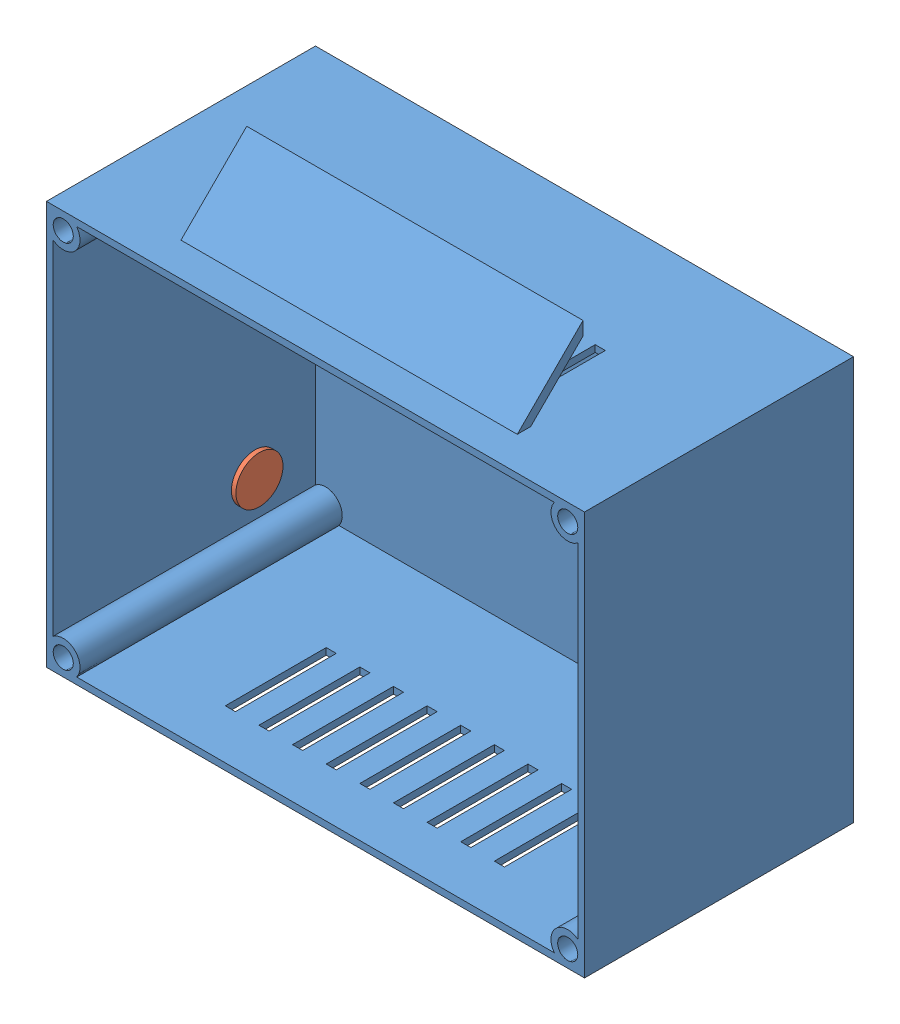
SolidWorks assembly Ensamblaje2, configuration Predeterminado. Lengths in mm.
Overall size (81.33 79.56 40).
2 component instances, 2 part files, 1 mates.
Components (placement in the parent):
- proyecto case-1: proyecto case [Predeterminado] at (32.2877 -7.4744 -20) size (80 79.56 40)
- conector-1: conector [Predeterminado] at (-6.0431 -27.4744 -10) x (0 0 1) z (-1 0 0) size (7 7 3)
Mates (geometry in assembly coordinates):
- Concéntrica1: concentric aligned: circle of proyecto case-1; circle of conector-1
